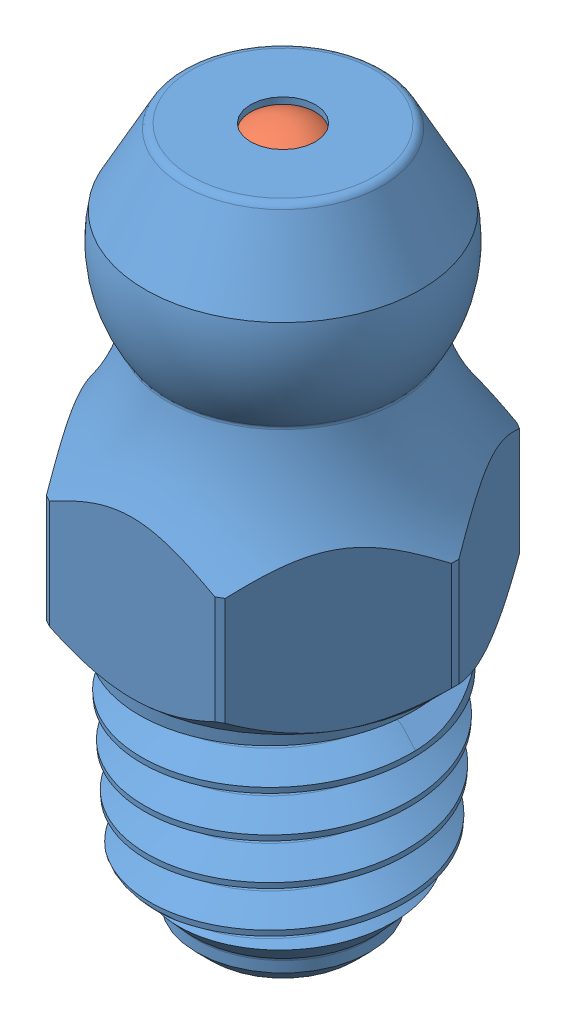
SolidWorks assembly Grease Nipple A M6x1.00, configuration Default. Lengths in mm.
Overall size (8.34 16.1 7).
2 component instances, 2 part files, 3 mates.
Components (placement in the parent):
- Grease Nipple A-1: Grease Nipple A [A M6x1.00] at origin size (8.34 16 7)
- Steel Ball-1: Steel Ball [Ø 2.50] at (0 1.1952 0) size (2.5 2.5 2.5)
Mates (geometry in assembly coordinates):
- Coincident1: coincident: circle of Grease Nipple A-1; sphere of Steel Ball-1
- Parallel1: parallel aligned: plane of Grease Nipple A-1 through (0 0 0) normal (0 0 1); plane of Steel Ball-1 through (0 1.1952 0) normal (0 0 1)
- Parallel2: parallel aligned: plane of Grease Nipple A-1 through (0 0 0) normal (0 1 0); plane of Steel Ball-1 through (0 1.1952 0) normal (0 1 0)
